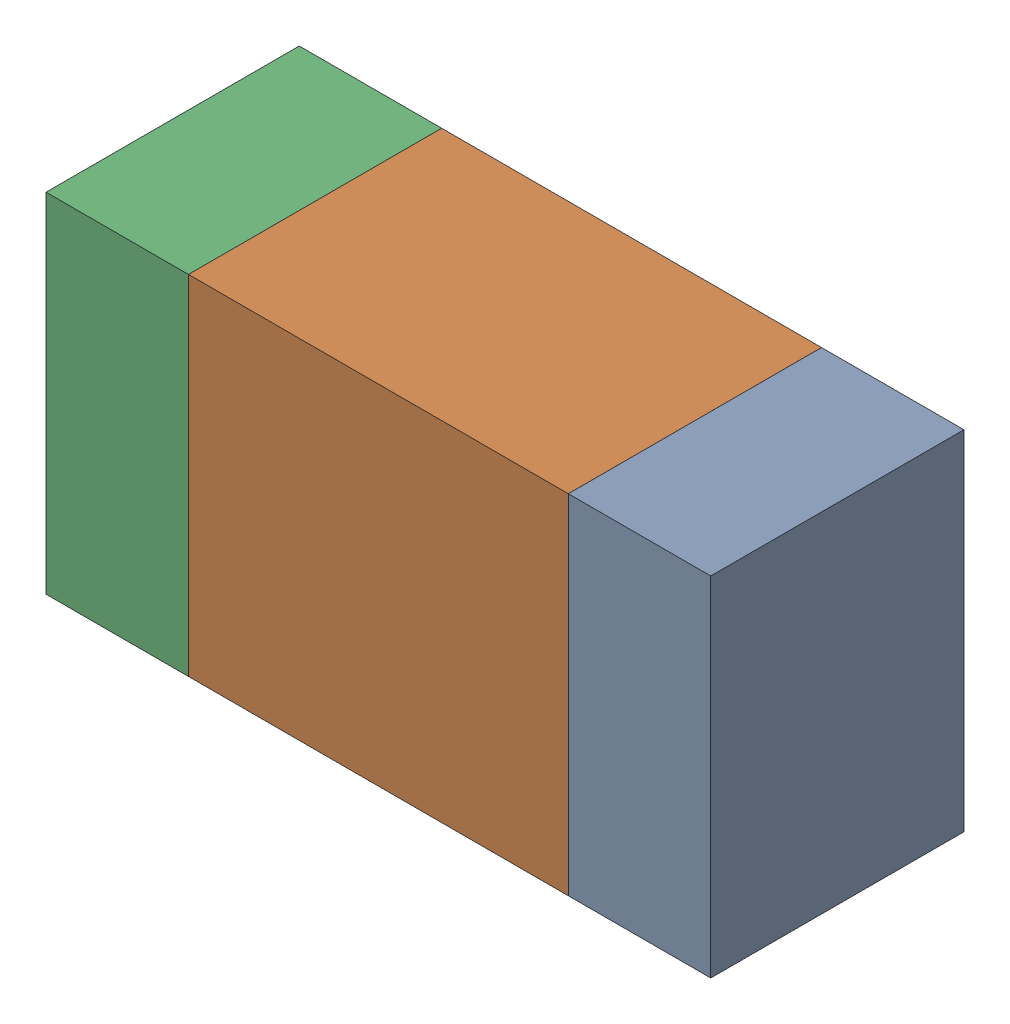
SolidWorks assembly R504_2PCB, configuration Default. Lengths in mm.
Overall size (1.05 0.55 0.4).
6 component instances, 2 part files, 0 mates.
Components (placement in the parent):
- 854785432-1: 854785432 [Default] at (156.8878 91.2681 0) size (0.22 0.55 0.4)
  - Extruded-1: Extruded [Default] at origin size (0.22 0.55 0.4)
- 854785568-1: 854785568 [Default] at (156.4753 91.2681 0) size (0.6 0.55 0.4)
  - Extruded_2-1: Extruded_2 [Default] at origin size (0.6 0.55 0.4)
- 854785432-2: 854785432 [Default] at (156.0628 91.2681 0) size (0.22 0.55 0.4)
  - Extruded-1: Extruded [Default] at origin size (0.22 0.55 0.4)
